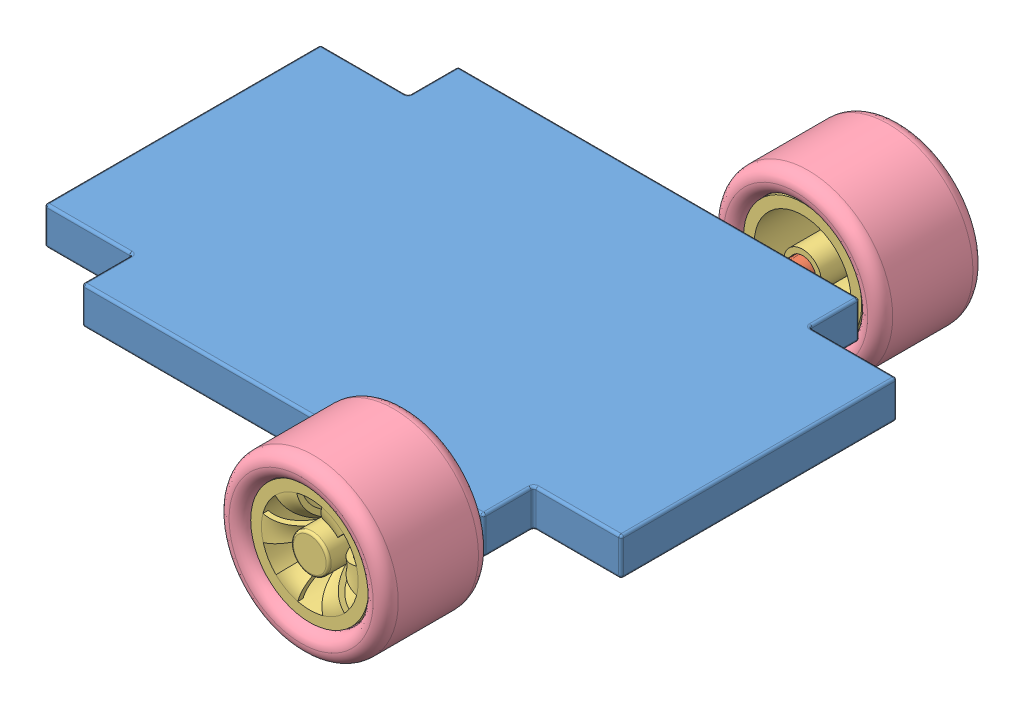
SolidWorks assembly Final Assembly, configuration Default. Lengths in mm.
Overall size (606.52 171.5 607.3).
9 component instances, 7 part files, 0 mates.
Components (placement in the parent):
- chassis-2: chassis [Default] at (57.9283 118.409 189.0195) x (1 0 0) z (0 -1 0) size (584.2 381 38.1)
- Part3^Final Assembly-1: Part3^Final Assembly [Default] at origin (virtual)
- axle-2: axle [Default] at (189.6119 98.1569 -33.0008) size (27.69 27.69 457.2)
- rim-3: rim [Default] at (190.5194 100.9537 446.5322) x (0 0 1) z (-1 0 0) size (76.2 119.74 119.74)
- rim-4: rim [Default] at (190.2954 99.7036 -52.8665) x (0 0 -1) z (-1 0 0) size (76.2 119.74 119.74)
- tyre_new-1: tyre_new [Default] at (189.9922 99.6756 386.2232) size (171.33 171.33 106.68)
- tyre_new-2: tyre_new [Default] at (190.2642 99.506 -114.3978) size (171.33 171.33 106.68)
- caster wheel-1: caster wheel [Default] at (-220.8038 55.5918 195.0365) x (0 0 -1) z (0 -1 0) size (17.12 71.37 71.37)
- caster wheel support-2: caster wheel support [Default] at (-237.761 50.7834 206.3436) x (0 0 -1) z (1 0 0) size (38.1 45.72 38.1)
